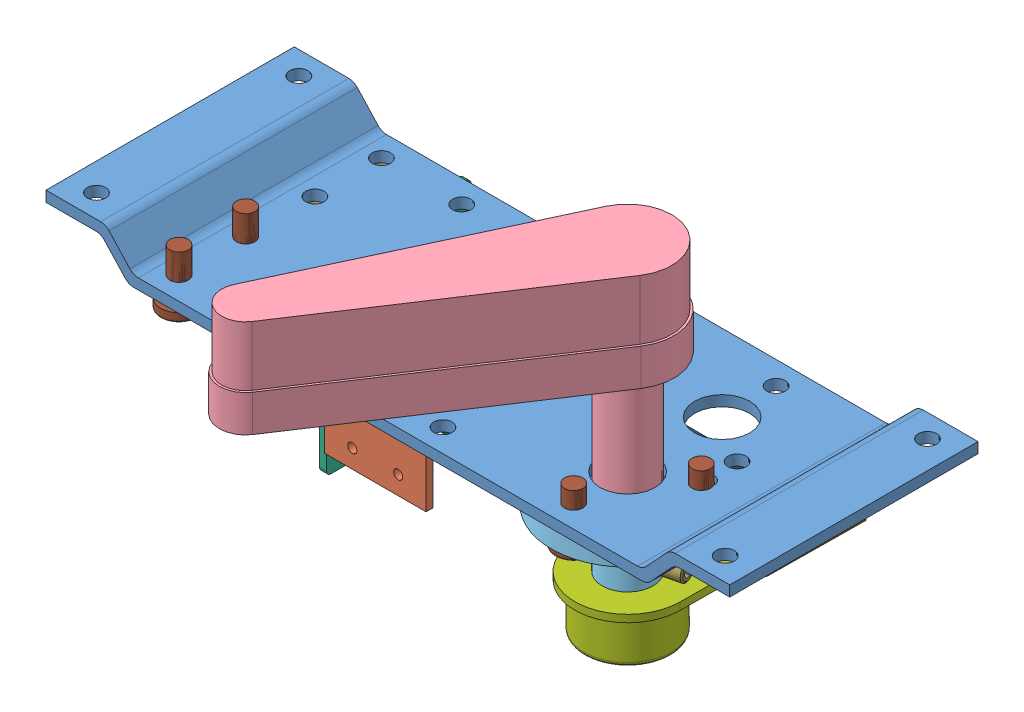
SolidWorks assembly Assemblage Batteur, configuration Défaut. Lengths in mm.
Overall size (149 86.78 104.17).
21 component instances, 12 part files, 41 mates.
Components (placement in the parent):
- Platine Batteur-1: Platine Batteur [Défaut] at (-121.9161 17.9387 -27.05) size (149 8.8 54.1)
- Support Switch-1: Support Switch [Défaut] at (-84.7411 9.1387 2.05) x (0 0 1) z (1 0 0) size (25 34 22.15)
- Support Bobine-1: Support Bobine [Défaut] at (-88.9161 9.1387 -25.85) x (0 0 1) z (1 0 0) size (22.1 25.5 14)
- Support Bobine-2: Support Bobine [Défaut] at (-49.4161 9.1387 -3.75) x (0 0 -1) z (-1 0 0) size (22.1 25.5 14)
- Flipper-1: Flipper [Défaut] at (-7.2218 55.1387 1.8965) x (-0.487687 0 0.873019) z (0 -1 0) size (77 20.25 76)
- Plastique Flipper-1: Plastique Flipper [Défaut] at (-11.9161 -7.3613 10.3) x (-0.5 0 -0.866025) z (0.866025 0 -0.5) size (33.2 16.5 33.2)
- Bobine Batteur-1: Bobine Batteur [Défaut] at (-86.9161 -6.3613 -14.8) x (0 0 1) z (1 0 0) size (31.5 40.79 38.2)
- Piece métalique gauche-1: Piece métalique gauche [Défaut] at (-11.9161 -8.9613 10.3) x (-0.007223 0 0.999974) z (-0.999974 0 -0.007223) size (43 24.5 30)
- Fourreau Batteur-1: Fourreau Batteur [Défaut] at (-45.0161 -6.3613 -14.8) x (0 0.28694 0.957949) z (-1 0 0) size (15.69 15.69 43.9)
- Piece composite-1: Piece composite [Défaut] at (-17.6931 -7.3613 -25.5331) x (-0.010876 0 0.999941) z (0 1 0) size (21.5 29.15 3.15)
- Plongeur Batteur-1: Plongeur Batteur [Défaut] at (-80.3099 -6.3613 -14.8) x (0 -1 0) z (1 0 0) size (11.1 11.1 65)
- pan head cross recess screw_iso-1: pan head cross recess screw_iso [ISO 7045 - M4 x 10 - Z --- 10C] at (-97.9161 4.0387 22.05) x (0 1 0) z (-0.185917 0 0.982566) size (13.02 8 8)
- pan head cross recess screw_iso-2: pan head cross recess screw_iso [ISO 7045 - M4 x 10 - Z --- 10C] at (-97.9161 4.0387 7.55) x (0 1 0) z (0.611823 0 0.790994) size (13.02 8 8)
- pan head cross recess screw_iso-3: pan head cross recess screw_iso [ISO 7045 - M4 x 10 - Z --- 10C] at (-11.9161 2.0387 22.05) x (0 1 0) z (-0.97364 0 0.228089) size (13.02 8 8)
- pan head cross recess screw_iso-4: pan head cross recess screw_iso [ISO 7045 - M4 x 10 - Z --- 10C] at (-1.7403 2.0387 4.425) x (0 1 0) z (0.724162 0 0.68963) size (13.02 8 8)
- pan head cross recess screw_iso-5: pan head cross recess screw_iso [ISO 7045 - M4 x 10 - Z --- 10C] at (-22.0919 2.0387 4.425) x (0 1 0) z (0.565898 0 0.824475) size (13.02 8 8)
- pan head cross recess screw_iso-6: pan head cross recess screw_iso [ISO 7045 - M4 x 10 - Z --- 10C] at (-40.4161 4.0387 -7.55) x (0 1 0) z (0.252137 0 0.967692) size (13.02 8 8)
- pan head cross recess screw_iso-7: pan head cross recess screw_iso [ISO 7045 - M4 x 10 - Z --- 10C] at (-40.4161 4.0387 -22.05) x (0 1 0) z (-0.264754 0 0.964316) size (13.02 8 8)
- pan head cross recess screw_iso-8: pan head cross recess screw_iso [ISO 7045 - M4 x 10 - Z --- 10C] at (-66.9161 4.5387 22.05) x (0 1 0) z (0.611823 0 0.790994) size (13.02 8 8)
- pan head cross recess screw_iso-9: pan head cross recess screw_iso [ISO 7045 - M4 x 10 - Z --- 10C] at (-80.4161 4.5387 22.05) x (0 1 0) z (0.264526 0 0.964379) size (13.02 8 8)
- socket set screw flat point_iso-2: socket set screw flat point_iso [ISO 4026 - M4 x 8-C] at (-1.2056 -3.3613 7.7931) x (-0.973685 0 0.227898) z (-0.227898 0 -0.973685) size (8 4 4)
Mates (geometry in assembly coordinates):
- Coïncidente4: coincident anti-aligned: plane of Platine Batteur-1 through (-102.8286 9.1387 27.05) normal (0 -1 0); plane of Support Switch-1 through (-62.5911 9.1387 3.1723) normal (0 1 0)
- Tangent1: tangent anti-aligned: cylinder of Flipper-1 through (-11.9161 9.1387 10.3) axis (0 -1 0) radius 3; plane of socket set screw flat point_iso-2 through (-8.9951 -2.1113 9.6163) normal (-0.973685 0 0.227898)
- Coaxiale27: concentric aligned: circle of Bobine Batteur-1; cylinder of Fourreau Batteur-1 through (-88.4161 -6.3613 -14.8) axis (1 0 0) radius 6.25
- Coïncidente5: coincident anti-aligned: plane of Bobine Batteur-1 through (-88.4161 -30.6463 -0.05) normal (-1 0 0); plane of Fourreau Batteur-1 through (-88.4161 -6.3613 -14.8) normal (1 0 0)
- Coaxiale28: concentric anti-aligned: cylinder of Fourreau Batteur-1 through (-88.4161 -6.3613 -14.8) axis (1 0 0) radius 5.75; cylinder of Plongeur Batteur-1 through (-15.3099 -6.3613 -14.8) axis (-1 0 0) radius 5.55
- Coaxiale29: concentric anti-aligned: cylinder of Platine Batteur-1 through (-11.9161 9.1387 10.3) axis (0 1 0) radius 6; cylinder of Plastique Flipper-1 through (-11.9161 -7.3613 10.3) axis (0 -1 0) radius 5.55
- Coïncidente6: coincident anti-aligned: cylinder of Platine Batteur-1 through (-11.9161 9.1387 22.05) axis (0 1 0) radius 2; circle of Plastique Flipper-1
- Coaxiale30: concentric aligned: cylinder of Flipper-1 through (-11.9161 9.1387 10.3) axis (0 -1 0) radius 3; cylinder of Plastique Flipper-1 through (-11.9161 -7.3613 10.3) axis (0 -1 0) radius 3.15
- Coïncidente8: coincident anti-aligned: plane of Flipper-1 through (-11.9161 9.1387 10.3) normal (0 -1 0); plane of Plastique Flipper-1 through (-20.2161 9.1387 -4.076) normal (0 1 0)
- Coaxiale33: concentric aligned: cylinder of Support Bobine-2 through (-49.4161 -6.3613 -14.8) axis (1 0 0) radius 6.25; cylinder of Fourreau Batteur-1 through (-88.4161 -6.3613 -14.8) axis (1 0 0) radius 5.75
- Coïncidente11: coincident anti-aligned: plane of Platine Batteur-1 through (-102.8286 9.1387 27.05) normal (0 -1 0); plane of Support Bobine-2 through (-46.4161 9.1387 -25.85) normal (0 1 0)
- Coaxiale41: concentric anti-aligned: cylinder of Platine Batteur-1 through (-40.4161 9.1387 -7.55) axis (0 1 0) radius 2; cylinder of Support Bobine-2 through (-40.4161 9.1387 -7.55) axis (0 -1 0) radius 2
- Coaxiale42: concentric aligned: circle of Platine Batteur-1; cylinder of Support Bobine-2 through (-40.4161 9.1387 -22.05) axis (0 -1 0) radius 2
- Coaxiale43: concentric aligned: cylinder of Piece composite-1 through (-19.3099 -4.2113 -14.8) axis (0 -1 0) radius 1.5; cylinder of Plongeur Batteur-1 through (-19.3099 -0.8113 -14.8) axis (0 -1 0) radius 1.5
- Parallèle1: parallel aligned: plane of Platine Batteur-1 through (-102.8286 9.1387 27.05) normal (0 -1 0); plane of Bobine Batteur-1 through (-88.4161 -31.6463 -0.05) normal (0 -1 0)
- Coaxiale44: concentric anti-aligned: cylinder of Platine Batteur-1 through (-80.4161 9.1387 22.05) axis (0 1 0) radius 2; cylinder of Support Switch-1 through (-80.4161 9.1387 22.05) axis (0 -1 0) radius 2
- Coaxiale45: concentric anti-aligned: cylinder of Platine Batteur-1 through (-66.9161 9.1387 22.05) axis (0 1 0) radius 2; cylinder of Support Switch-1 through (-66.9161 9.1387 22.05) axis (0 -1 0) radius 2
- Coaxiale46: concentric aligned: cylinder of Support Bobine-2 through (-40.4161 9.1387 -7.55) axis (0 -1 0) radius 2; cylinder of pan head cross recess screw_iso-6 through (-40.4161 -21.3613 -7.55) axis (0 -1 0) radius 2
- Coïncidente22: coincident anti-aligned: plane of Support Bobine-2 through (-45.9161 7.1387 -25.85) normal (0 -1 0); plane of pan head cross recess screw_iso-6 through (-42.3515 7.1387 -7.0457) normal (0 1 0)
- Coaxiale47: concentric aligned: cylinder of Support Bobine-2 through (-40.4161 9.1387 -22.05) axis (0 -1 0) radius 2; cylinder of pan head cross recess screw_iso-7 through (-40.4161 -21.3613 -22.05) axis (0 -1 0) radius 2
- Coïncidente23: coincident aligned: plane of Support Bobine-2 through (-45.9161 7.1387 -25.85) normal (0 -1 0); circle of pan head cross recess screw_iso-7
- Coïncidente24: coincident anti-aligned: plane of Platine Batteur-1 through (-102.8286 9.1387 27.05) normal (0 -1 0); plane of Plastique Flipper-1 through (-20.2161 9.1387 -4.076) normal (0 1 0)
- Coaxiale49: concentric aligned: cylinder of Plastique Flipper-1 through (-22.0919 9.1387 4.425) axis (0 -1 0) radius 2; cylinder of pan head cross recess screw_iso-5 through (-22.0919 -23.3613 4.425) axis (0 -1 0) radius 2
- Coïncidente26: coincident anti-aligned: plane of Plastique Flipper-1 through (-15.9411 5.1387 3.3285) normal (0 -1 0); plane of pan head cross recess screw_iso-5 through (-23.7409 5.1387 5.5568) normal (0 1 0)
- Coaxiale50: concentric aligned: cylinder of Plastique Flipper-1 through (-1.7403 9.1387 4.425) axis (0 -1 0) radius 2; cylinder of pan head cross recess screw_iso-4 through (-1.7403 -23.3613 4.425) axis (0 -1 0) radius 2
- Coïncidente27: coincident anti-aligned: plane of Plastique Flipper-1 through (-15.9411 5.1387 3.3285) normal (0 -1 0); plane of pan head cross recess screw_iso-4 through (-3.1196 5.1387 5.8733) normal (0 1 0)
- Coaxiale51: concentric aligned: cylinder of Plastique Flipper-1 through (-11.9161 9.1387 22.05) axis (0 -1 0) radius 2; cylinder of pan head cross recess screw_iso-3 through (-11.9161 -23.3613 22.05) axis (0 -1 0) radius 2
- Coïncidente28: coincident anti-aligned: plane of Plastique Flipper-1 through (-15.9411 5.1387 3.3285) normal (0 -1 0); plane of pan head cross recess screw_iso-3 through (-12.3723 5.1387 20.1027) normal (0 1 0)
- Coaxiale52: concentric aligned: circle of Support Switch-1; cylinder of pan head cross recess screw_iso-9 through (-80.4161 -20.8613 22.05) axis (0 -1 0) radius 2
- Coïncidente30: coincident anti-aligned: plane of Support Switch-1 through (-62.5911 7.6387 4.6723) normal (0 -1 0); plane of pan head cross recess screw_iso-9 through (-82.3449 7.6387 22.5791) normal (0 1 0)
- Coaxiale53: concentric aligned: cylinder of Support Switch-1 through (-66.9161 9.1387 22.05) axis (0 -1 0) radius 2; cylinder of pan head cross recess screw_iso-8 through (-66.9161 -20.8613 22.05) axis (0 -1 0) radius 2
- Coïncidente31: coincident anti-aligned: plane of Support Switch-1 through (-62.5911 7.6387 4.6723) normal (0 -1 0); plane of pan head cross recess screw_iso-8 through (-68.4981 7.6387 23.2736) normal (0 1 0)
- Coaxiale54: concentric anti-aligned: cylinder of Platine Batteur-1 through (-97.9161 9.1387 -22.05) axis (0 1 0) radius 2; cylinder of Support Bobine-1 through (-97.9161 9.1387 -22.05) axis (0 -1 0) radius 2
- Coaxiale55: concentric anti-aligned: cylinder of Platine Batteur-1 through (-97.9161 9.1387 -7.55) axis (0 1 0) radius 2; cylinder of Support Bobine-1 through (-97.9161 9.1387 -7.55) axis (0 -1 0) radius 2
- Coïncidente32: coincident anti-aligned: plane of Platine Batteur-1 through (-102.8286 9.1387 27.05) normal (0 -1 0); plane of Support Bobine-1 through (-91.9161 9.1387 -3.75) normal (0 1 0)
- Coïncidente33: coincident anti-aligned: plane of Support Bobine-1 through (-88.9161 -16.3613 -3.75) normal (1 0 0); circle of Fourreau Batteur-1
- Coaxiale56: concentric aligned: cylinder of Flipper-1 through (-11.9161 9.1387 10.3) axis (0 -1 0) radius 3; cylinder of Piece métalique gauche-1 through (-11.9161 -7.3613 10.3) axis (0 -1 0) radius 3.15
- Coïncidente34: coincident anti-aligned: plane of Plastique Flipper-1 through (-13.4911 -7.3613 7.572) normal (0 -1 0); plane of Piece métalique gauche-1 through (-11.9161 -7.3613 10.3) normal (0 1 0)
- Coïncidente35: coincident anti-aligned: plane of Piece métalique gauche-1 through (-11.9161 -7.3613 10.3) normal (0 1 0); plane of Piece composite-1 through (-17.6931 -7.3613 -25.5331) normal (0 -1 0)
- Coaxiale57: concentric aligned: circle of Piece métalique gauche-1; circle of Piece composite-1
- Verrouiller2: lock: unknown of Flipper-1; unknown of Piece métalique gauche-1
